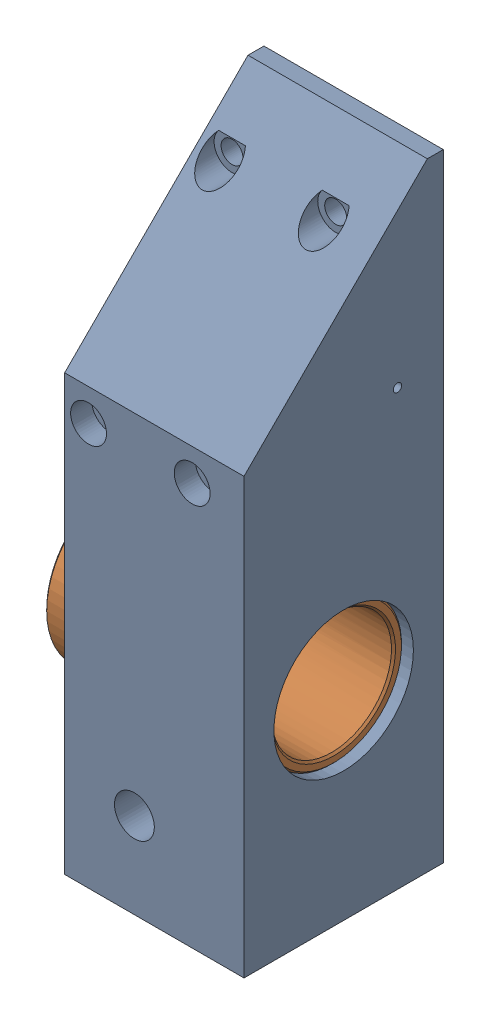
SolidWorks assembly Предварительная сборка, configuration По умолчанию. Lengths in mm.
Overall size (110 310 100).
2 component instances, 2 part files, 2 mates.
Components (placement in the parent):
- Корпус заготовка-1: Корпус заготовка [По умолчанию] at (-11.9962 13.339 1000) size (90 310 100)
- Втулка корпуса-1: Втулка корпуса [По умолчанию] at (-31.9962 -41.661 1000) size (105 80 80)
Mates (geometry in assembly coordinates):
- Концентричный1: concentric: cylinder of Корпус заготовка-1 through (78.0038 -41.661 1000) axis (-1 0 0) radius 35; cylinder of Втулка корпуса-1 through (-31.9962 -41.661 1000) axis (-1 0 0) radius 35
- Совпадение1: coincident anti-aligned: plane of Корпус заготовка-1 through (-11.9962 13.339 1000) normal (-1 0 0); plane of Втулка корпуса-1 through (-11.9962 -6.661 1000) normal (1 0 0)
